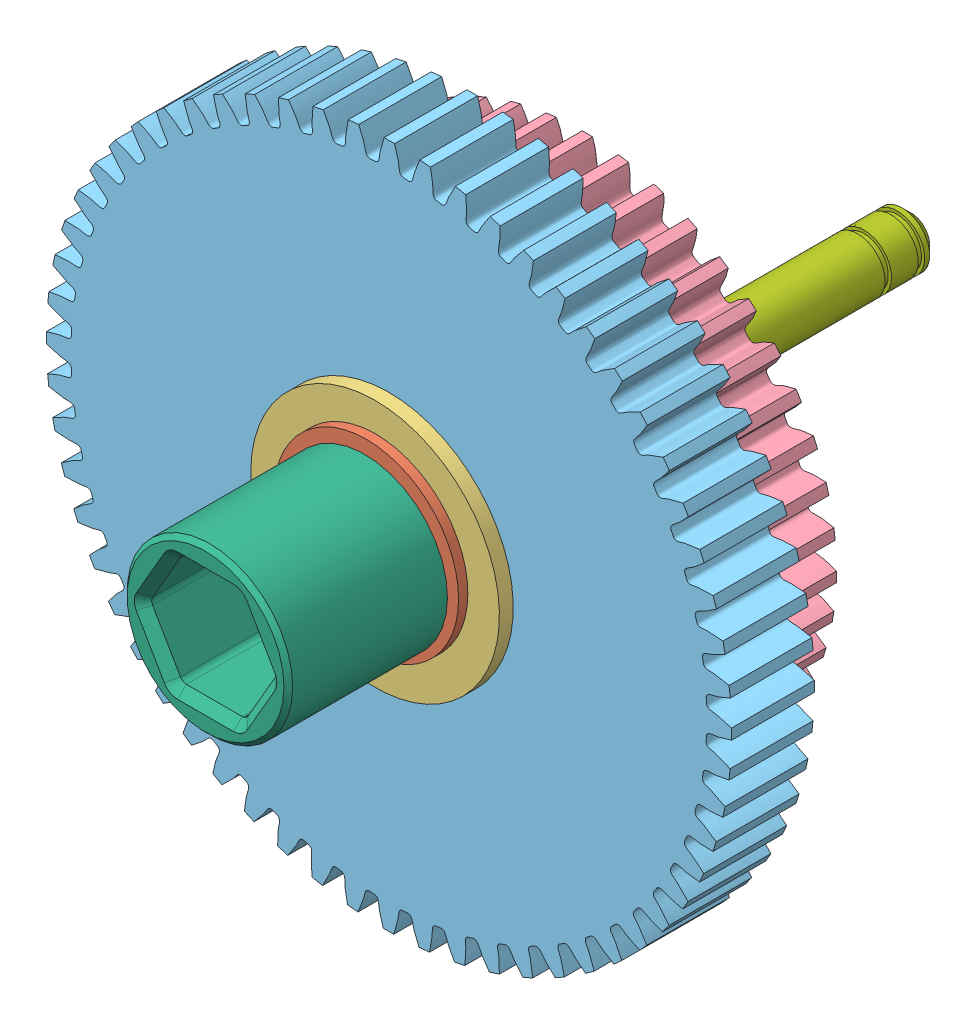
SolidWorks assembly 217-2792-001 Rev1, configuration Default. Lengths in mm.
Overall size (82.92 82.92 81.07).
17 component instances, 8 part files, 0 mates.
Components (placement in the parent):
- 217-2428-008 Rev1-1: 217-2428-008 Rev1 [Default] at (0 0 10.2679) size (31.75 31.75 1.59)
- 217-2428-028 Rev1_97633A250-1: 217-2428-028 Rev1_97633A250 [Default] at (0 0 37.1221) x (0 0 1) z (0.9357 -0.352797 0) size (1.07 23.39 21.18)
- 217-2709-101 Rev1-1: 217-2709-101 Rev1 [Default] at (0 0 20.7137) x (0.993517 0.113685 0) z (0 0 -1) size (62.31 62.31 12.7)
  - 217-2428-022 Rev1-1: 217-2428-022 Rev1 [Default] at origin size (28.57 28.57 6.1)
  - 217-2709-001_44t Steel-1: 217-2709-001_44t Steel [Default] at (0 0 3.302) x (0.062728 -0.998031 0) z (0 0 1) size (58.74 58.74 11.11)
- 217-2713-101 Rev1-1: 217-2713-101 Rev1 [Default] at (0 0 33.4137) x (-0.01285 0.999917 0) z (0 0 -1) size (81.88 81.88 12.7)
  - 217-2713-001_60t Steel-1: 217-2713-001_60t Steel [Default] at (0 0 3.302) x (0.999266 -0.038302 0) z (0 0 1) size (78.91 78.91 11.11)
  - 217-2428-022 Rev1-1: 217-2428-022 Rev1 [Default] at origin size (28.57 28.57 6.1)
- 217-2790-001 Rev1-1: 217-2790-001 Rev1 [Default] x (-1 0 0) z (0 0 1) size (22.23 22.23 81.07)
  - 217-2790-003 Rev1-1: 217-2790-003 Rev1 [Default] at origin size (22.23 22.23 55.94)
  - 217-2790-004 Rev1-1: 217-2790-004 Rev1 [Default] at (0 0 14.3911) x (0.928141 0.372229 0) z (0 0 1) size (11.68 11.68 44.12)
- 217-2428-007 Rev1-1: 217-2428-007 Rev1 [Default] at (6.3246 0 14.2494) x (0.485433 0.3648 -0.794529) z (-0.690104 -0.398066 -0.6044) size (6.35 6.35 6.35)
- 217-2428-007 Rev1-2: 217-2428-007 Rev1 [Default] at (9.017 0 26.9494) x (0.741485 -0.614816 -0.268704) z (-0.150074 0.23836 -0.959512) size (6.35 6.35 6.35)
- 217-2428-007 Rev1-3: 217-2428-007 Rev1 [Default] at (-3.1623 5.4773 14.2494) x (-0.558642 0.237997 -0.794529) z (0.689788 -0.398615 -0.6044) size (6.35 6.35 6.35)
- 217-2428-007 Rev1-4: 217-2428-007 Rev1 [Default] at (-3.1623 -5.4773 14.2494) x (0.073209 -0.602797 -0.794529) z (0.000317 0.796681 -0.6044) size (6.35 6.35 6.35)
- 217-2428-007 Rev1-5: 217-2428-007 Rev1 [Default] at (-4.5085 7.809 26.9494) x (0.161703 0.949553 -0.268704) z (-0.131389 -0.249147 -0.959512) size (6.35 6.35 6.35)
- 217-2428-007 Rev1-6: 217-2428-007 Rev1 [Default] at (-4.5085 -7.809 26.9494) x (-0.903188 -0.334737 -0.268704) z (0.281462 0.010788 -0.959512) size (6.35 6.35 6.35)
